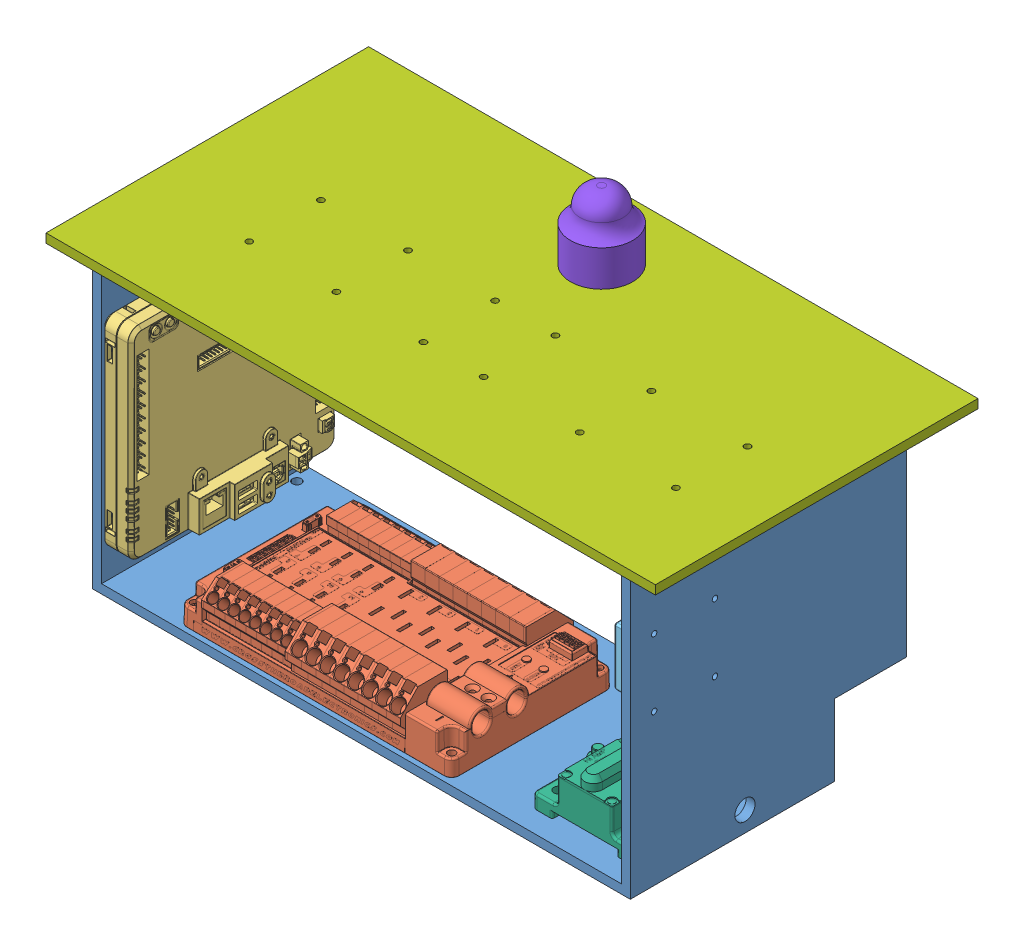
SolidWorks assembly Final Final Final design, configuration Default. Lengths in mm.
Overall size (431.8 257.81 228.6).
15 component instances, 9 part files, 20 mates.
Components (placement in the parent):
- bottom board-1: bottom board [Default] at (-127.8625 213.8755 561.2447) size (381 203.2 195.58)
- PDP-1: PDP [Default] at (22.4547 226.9057 215.9317) x (-1 0 0) z (0 0 -1) size (192.68 36.15 120.93)
- Roborio-1: Roborio [Default] at (-111.8605 313.1831 203.6889) x (0 0 1) z (1 0 0) size (146.27 143.19 36.83)
- radio b;ock-1: radio b;ock [Default] at (246.7875 391.6755 189.1347) x (0 0 -1) z (0 1 0) size (69.85 25.4 95.25)
- VRM-1: VRM [Default] at (239.6816 345.0823 236.4676) x (0 1 0) z (0 0 1) size (56.39 19.92 51.56)
- Breaker-1: Breaker [Default] at (205.5125 225.0515 237.3947) x (-1 0 0) z (0 0 -1) size (73.72 42.2 48.95)
- New and Improved Signal Light board-2: New and Improved Signal Light board [Default] at (278.5375 417.0755 55.7847) x (-1 0 0) z (0 0 -1) size (431.8 79.12 228.6)
  - Signal light board-1: Signal light board [Default] at origin size (431.8 6.35 228.6)
  - signal light-1: signal light [Default] at (215.9 31.75 -50.8) x (-0.837169 0 -0.546944) z (-0.546944 0 0.837169) size (43.94 79.12 43.94)
  - Speed Controller-2: Speed Controller [Default] at (52.2328 -8.5448 -136.4813) x (1 0 0) z (0 -1 0) size (30.12 70.11 24.39)
  - Speed Controller-3: Speed Controller [Default] at (120.3149 -8.5448 -136.4813) x (1 0 0) z (0 -1 0) size (30.12 70.11 24.39)
  - Speed Controller-4: Speed Controller [Default] at (188.397 -8.5448 -136.4813) x (1 0 0) z (0 -1 0) size (30.12 70.11 24.39)
  - Speed Controller-5: Speed Controller [Default] at (231.079 -8.5448 -136.4813) x (1 0 0) z (0 -1 0) size (30.12 70.11 24.39)
  - Speed Controller-6: Speed Controller [Default] at (292.8111 -8.5448 -136.4813) x (1 0 0) z (0 -1 0) size (30.12 70.11 24.39)
  - Speed Controller-7: Speed Controller [Default] at (354.5432 -8.5448 -136.4813) x (1 0 0) z (0 -1 0) size (30.12 70.11 24.39)
Mates (geometry in assembly coordinates):
- Coincident1: coincident anti-aligned: plane of bottom board-1 through (-127.8625 220.2255 561.2447) normal (0 1 0); plane of PDP-1 through (-69.5695 220.2255 158.5277) normal (0 -1 0)
- Coincident25: coincident anti-aligned: plane of bottom board-1 through (-127.8625 220.2255 561.2447) normal (0 1 0); plane of Breaker-1 through (174.99 220.2255 257.7654) normal (0 -1 0)
- Distance14: distance = 38.1 mm aligned: plane of radio b;ock-1 through (221.3875 391.6755 119.2847) normal (0 0 -1); plane of bottom board-1 through (-127.8625 213.8755 81.1847) normal (0 0 -1)
- Coincident31: coincident anti-aligned: plane of bottom board-1 through (246.7875 391.6755 131.9847) normal (-1 0 0); plane of radio b;ock-1 through (246.7875 391.6755 189.1347) normal (1 0 0)
- Distance16: distance = 25.4 mm aligned: plane of radio b;ock-1 through (221.3875 391.6755 189.1347) normal (0 1 0); plane of bottom board-1 through (-127.8625 417.0755 561.2447) normal (0 1 0)
- Distance17: distance = 19.05 mm aligned: plane of VRM-1 through (226.8883 341.4553 257.7147) normal (0 0 1); plane of bottom board-1 through (-127.8625 213.8755 276.7647) normal (0 0 1)
- Distance18: distance = 50.8 mm aligned: plane of VRM-1 through (226.8883 366.2755 244.9604) normal (0 1 0); plane of bottom board-1 through (-127.8625 417.0755 561.2447) normal (0 1 0)
- Coincident41: coincident anti-aligned: plane of bottom board-1 through (246.7875 391.6755 131.9847) normal (-1 0 0); plane of VRM-1 through (246.7875 368.4267 216.9204) normal (1 0 0)
- Coincident42: coincident aligned: plane of bottom board-1 through (-121.5125 378.9755 131.9847) normal (1 0 0); plane of Roborio-1 through (-121.5125 385.1497 130.1769) normal (1 0 0)
- Coincident43: coincident anti-aligned: plane of bottom board-1 through (-127.8625 417.0755 561.2447) normal (0 1 0); plane of New and Improved Signal Light board-2/Signal light board-1 through (278.5375 417.0755 55.7847) normal (0 -1 0)
- Distance23: distance = 7.62 mm aligned: plane of New and Improved Signal Light board-2/Signal light board-1 through (278.5375 423.4255 284.3847) normal (0 0 1); plane of bottom board-1 through (-127.8625 213.8755 276.7647) normal (0 0 1)
- Distance26: distance = 25.4 mm aligned: plane of New and Improved Signal Light board-2/Signal light board-1 through (-153.2625 423.4255 55.7847) normal (-1 0 0); plane of bottom board-1 through (-127.8625 220.2255 561.2447) normal (-1 0 0)
- Concentric1: concentric anti-aligned: circle of bottom board-1; circle of PDP-1
- Concentric2: concentric anti-aligned: circle of bottom board-1; circle of PDP-1
- Concentric3: concentric anti-aligned: circle of bottom board-1; circle of PDP-1
- Concentric4: concentric anti-aligned: circle of bottom board-1; circle of PDP-1
- Concentric5: concentric anti-aligned: cylinder of bottom board-1 through (176.9375 202.4455 251.3647) axis (0 1 0) radius 3.175; cylinder of Breaker-1 through (176.9375 230.1315 251.3647) axis (0 -1 0) radius 3.429
- Concentric6: concentric anti-aligned: cylinder of bottom board-1 through (234.0875 202.4455 223.4247) axis (0 1 0) radius 3.175; cylinder of Breaker-1 through (234.0875 230.1315 223.4247) axis (0 -1 0) radius 3.429
- Distance27: distance = 6.35 mm aligned: plane of Roborio-1 through (-110.6392 241.5932 271.7629) normal (0 1 0); cylinder of bottom board-1 through (-118.9725 228.0995 195.4847) axis (-1 0 0) radius 7.1437
- Coincident47: coincident anti-aligned: plane of bottom board-1 through (-127.8625 213.8755 276.7647) normal (0 0 1); plane of Roborio-1 through (-119.2803 379.7118 276.7647) normal (0 0 -1)
